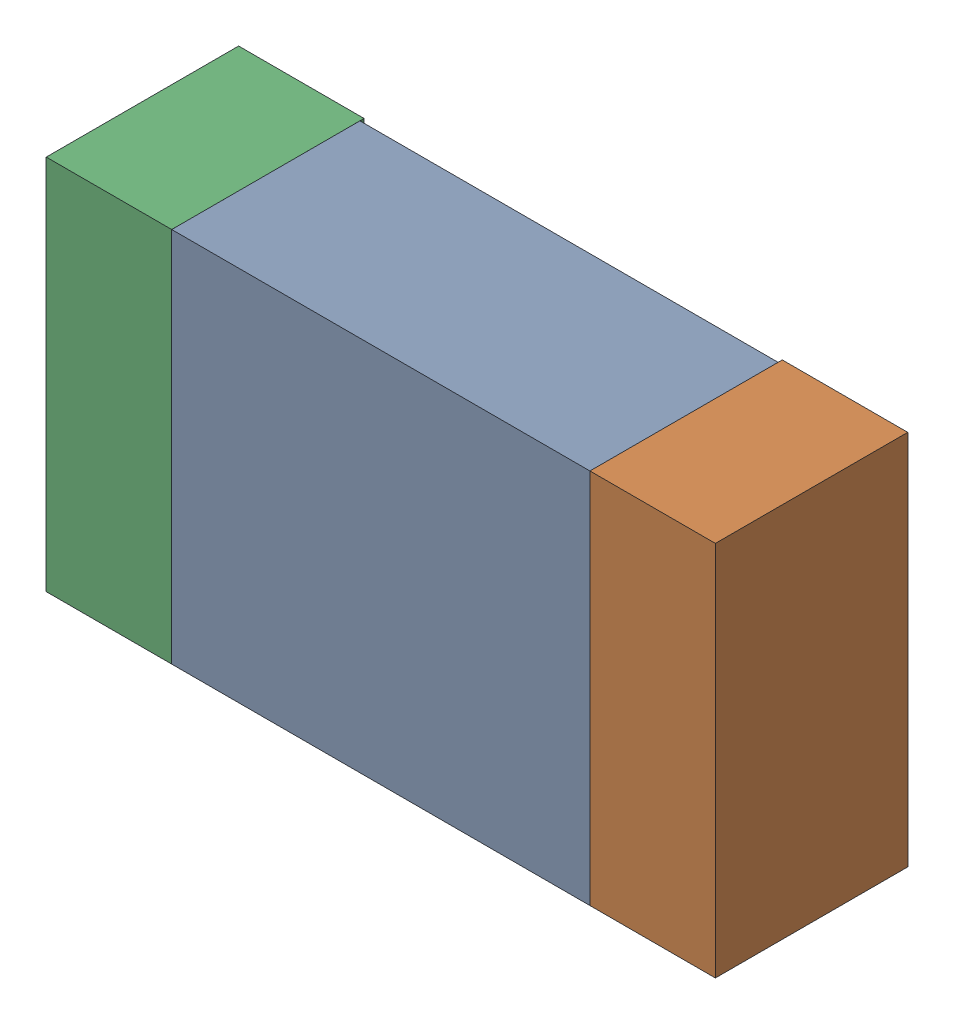
SolidWorks assembly L7, configuration Default. Lengths in mm.
Overall size (1.6 0.9 0.46).
6 component instances, 2 part files, 0 mates.
Components (placement in the parent):
- 870942240-1: 870942240 [Default] at (75.692 25.273 -2.0506) size (1 0.9 0.45)
  - Extruded_14-1: Extruded_14 [Default] at origin size (1 0.9 0.45)
- 870942080-1: 870942080 [Default] at (76.342 25.273 -2.0606) size (0.3 0.9 0.46)
  - Extruded_15-1: Extruded_15 [Default] at origin size (0.3 0.9 0.46)
- 870942080-2: 870942080 [Default] at (75.042 25.273 -2.0606) size (0.3 0.9 0.46)
  - Extruded_15-1: Extruded_15 [Default] at origin size (0.3 0.9 0.46)
